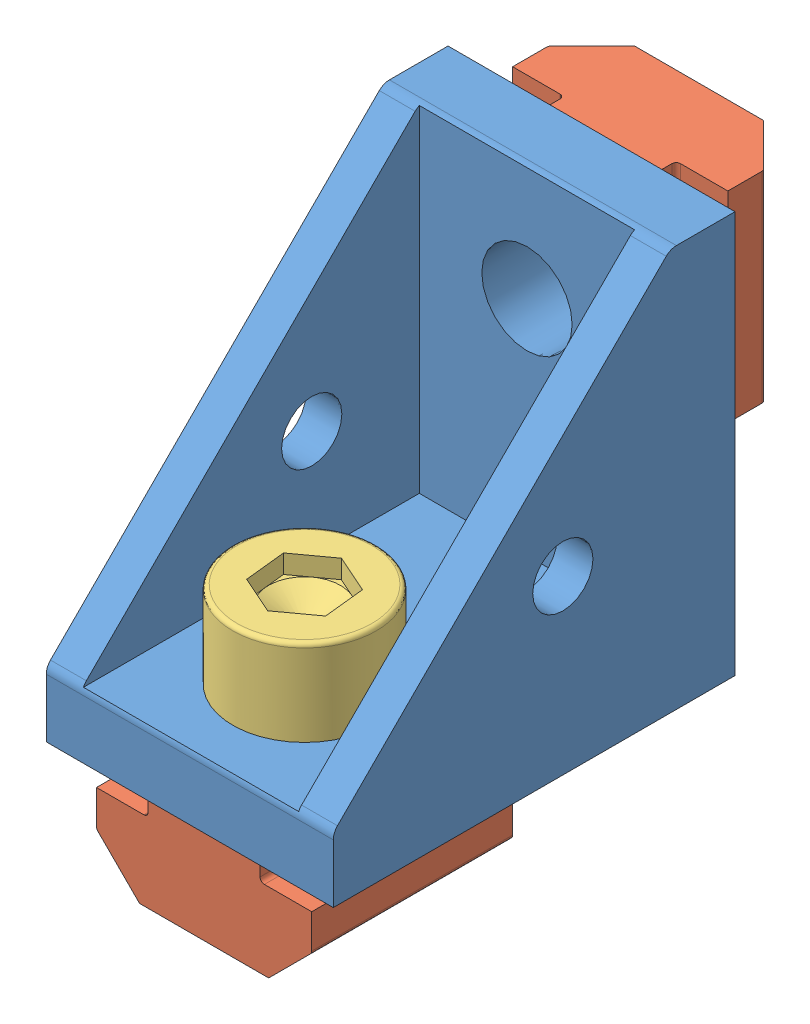
SolidWorks assembly HBLFSB6-C-SET, configuration Default. Lengths in mm.
Overall size (20 35.5 35.5).
5 component instances, 3 part files, 10 mates.
Components (placement in the parent):
- HBLFSB6-C-1: HBLFSB6-C [Default] at origin size (20 29 29)
- HNTT6-6-1: HNTT6-6 [Default] at (0 20 -2) size (15 14 6.5)
- HNTT6-6-2: HNTT6-6 [Default] at (0 -2 20) x (1 0 0) z (0 1 0) size (15 14 6.5)
- Socket head cap screw-1: Socket head cap screw [M6x12] at (0 10.5 20) x (0 -1 0) z (0.58869 0 0.808359) size (18 10 10)
- Socket head cap screw-2: Socket head cap screw [M6x12] at (0 20 10.5) x (0 0 -1) z (1 0 0) size (18 10 10)
Mates (geometry in assembly coordinates):
- Concentric1: concentric anti-aligned: cylinder of HBLFSB6-C-1 through (0 20 4.5) axis (0 0 1) radius 3.15; cylinder of HNTT6-6-1 through (0 20 -7.5) axis (0 0 -1) radius 2.5
- Coincident3: coincident anti-aligned: plane of HBLFSB6-C-1 through (0 0 -1) normal (0 0 -1); plane of HNTT6-6-1 through (0 20 -1) normal (0 0 1)
- Parallel2: parallel aligned: plane of HBLFSB6-C-1 through (-7.5 28 28) normal (0 1 0); plane of HNTT6-6-1 through (7.5 27 -7.5) normal (0 1 0)
- Concentric2: concentric anti-aligned: cylinder of HBLFSB6-C-1 through (0 4.5 20) axis (0 1 0) radius 3.15; cylinder of HNTT6-6-2 through (0 -7.5 20) axis (0 -1 0) radius 2.5
- Coincident5: coincident anti-aligned: plane of HBLFSB6-C-1 through (0 -1 0) normal (0 -1 0); plane of HNTT6-6-2 through (0 -1 20) normal (0 1 0)
- Parallel3: parallel aligned: plane of HBLFSB6-C-1 through (0 0 28) normal (0 0 1); plane of HNTT6-6-2 through (7.5 -7.5 27) normal (0 0 1)
- Concentric3: concentric aligned: cylinder of HBLFSB6-C-1 through (0 4.5 20) axis (0 1 0) radius 3.15; cylinder of Socket head cap screw-1 through (0 42.25 20) axis (0 1 0) radius 3
- Coincident7: coincident anti-aligned: plane of HBLFSB6-C-1 through (0 4.5 0) normal (0 1 0); plane of Socket head cap screw-1 through (4.0418 4.5 17.0565) normal (0 -1 0)
- Concentric4: concentric aligned: cylinder of HBLFSB6-C-1 through (0 20 4.5) axis (0 0 1) radius 3.15; cylinder of Socket head cap screw-2 through (0 20 42.25) axis (0 0 1) radius 3
- Coincident8: coincident anti-aligned: plane of HBLFSB6-C-1 through (7.5 4.5 4.5) normal (0 0 1); plane of Socket head cap screw-2 through (0 25 4.5) normal (0 0 -1)
